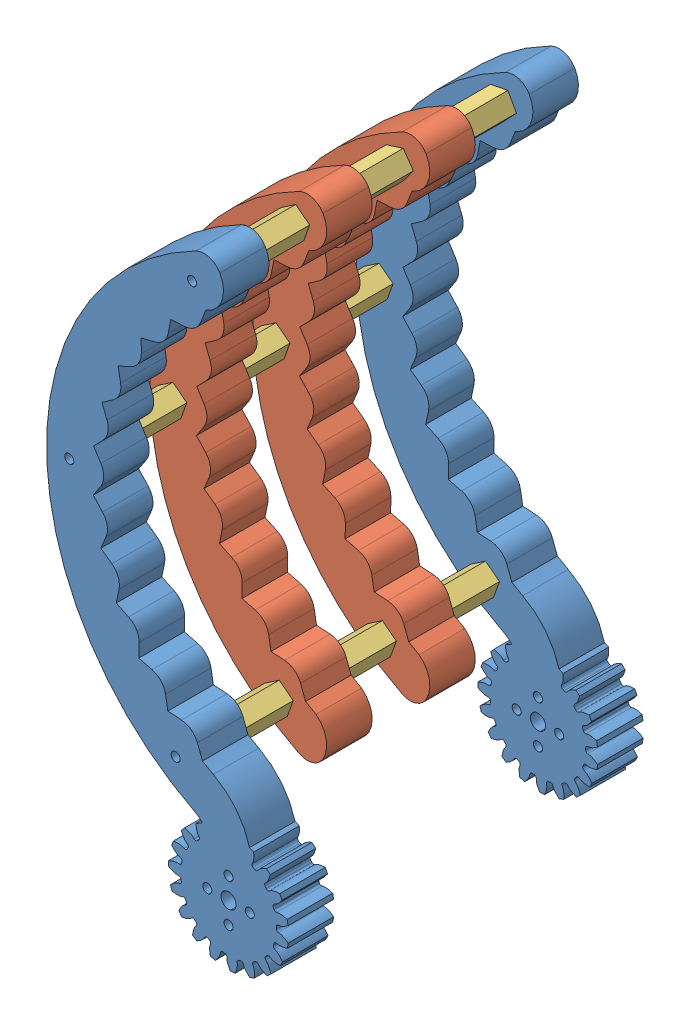
SolidWorks assembly 装配体_左爪子, configuration Default. Lengths in mm.
Overall size (79.66 200.49 117).
13 component instances, 3 part files, 27 mates.
Components (placement in the parent):
- 1_1.左爪子表面_打印两个-1: 1_1.左爪子表面_打印两个 [Varsayılan] at origin size (79.66 200.49 15)
- 1_3.爪子中间_打印四个-1: 1_3.爪子中间_打印四个 [Varsayılan] at (-2.9202 8.1355 -34) size (58.35 161.77 15)
- 2.铜柱连接件-1: 2.铜柱连接件 [Varsayılan] at (-28.6612 -59.3847 -21.5) x (0.366858 -0.930277 0) z (0 0 1) size (9.37 9.17 19)
- 2.铜柱连接件-2: 2.铜柱连接件 [Varsayılan] at (-63.7311 8.1181 -21.5) x (0.366858 -0.930277 0) z (0 0 1) size (9.37 9.17 19)
- 2.铜柱连接件-3: 2.铜柱连接件 [Varsayılan] at (-23.232 79.1263 -21.5) x (0.366858 -0.930277 0) z (0 0 1) size (9.37 9.17 19)
- 2.铜柱连接件-4: 2.铜柱连接件 [Varsayılan] at (-23.232 79.1263 -55.5) x (-0.923835 -0.38279 0) z (0 0 1) size (9.37 9.17 19)
- 2.铜柱连接件-5: 2.铜柱连接件 [Varsayılan] at (-63.7311 8.1181 -55.5) x (0.366858 -0.930277 0) z (0 0 1) size (9.37 9.17 19)
- 2.铜柱连接件-6: 2.铜柱连接件 [Varsayılan] at (-28.6612 -59.3847 -55.5) x (0.366858 -0.930277 0) z (0 0 1) size (9.37 9.17 19)
- 2.铜柱连接件-7: 2.铜柱连接件 [Varsayılan] at (-28.6612 -59.3847 -89.5) x (0.366858 -0.930277 0) z (0 0 1) size (9.37 9.17 19)
- 2.铜柱连接件-8: 2.铜柱连接件 [Varsayılan] at (-23.232 79.1263 -89.5) x (-0.960896 -0.276909 0) z (0 0 1) size (9.37 9.17 19)
- 2.铜柱连接件-9: 2.铜柱连接件 [Varsayılan] at (-63.7311 8.1181 -89.5) x (0.366858 -0.930277 0) z (0 0 1) size (9.37 9.17 19)
- 1_3.爪子中间_打印四个-2: 1_3.爪子中间_打印四个 [Varsayılan] at (-2.9202 8.1355 -68) size (58.35 161.77 15)
- 1_1.左爪子表面_打印两个-2: 1_1.左爪子表面_打印两个 [Varsayılan] at (0 0 -102) size (79.66 200.49 15)
Mates (geometry in assembly coordinates):
- 同心1: concentric aligned: cylinder of 1_1.左爪子表面_打印两个-1 through (-28.6612 -59.3847 -1) axis (0 0 -1) radius 1.5; cylinder of 2.铜柱连接件-1 through (-28.6612 -59.3847 -2.5) axis (0 0 -1) radius 2.5
- 重合1: coincident anti-aligned: plane of 1_1.左爪子表面_打印两个-1 through (-26.033 70.9061 -2.5) normal (0 0 -1); plane of 2.铜柱连接件-1 through (-28.6612 -59.3847 -2.5) normal (0 0 1)
- 重合2: coincident anti-aligned: plane of 1_1.左爪子表面_打印两个-1 through (-26.033 70.9061 -2.5) normal (0 0 -1); plane of 2.铜柱连接件-2 through (-63.7311 8.1181 -2.5) normal (0 0 1)
- 同心2: concentric anti-aligned: cylinder of 1_1.左爪子表面_打印两个-1 through (-63.7311 8.1181 -1) axis (0 0 -1) radius 1.5; circle of 2.铜柱连接件-2
- 同心3: concentric aligned: cylinder of 1_1.左爪子表面_打印两个-1 through (-23.232 79.1263 -1) axis (0 0 -1) radius 1.5; cylinder of 2.铜柱连接件-3 through (-23.232 79.1263 -2.5) axis (0 0 -1) radius 2.5
- 重合3: coincident anti-aligned: plane of 1_1.左爪子表面_打印两个-1 through (-26.033 70.9061 -2.5) normal (0 0 -1); plane of 2.铜柱连接件-3 through (-23.232 79.1263 -2.5) normal (0 0 1)
- 重合4: coincident anti-aligned: plane of 1_3.爪子中间_打印四个-1 through (-26.033 70.9061 -21.5) normal (0 0 1); plane of 2.铜柱连接件-3 through (-23.232 79.1263 -21.5) normal (0 0 -1)
- 同心4: concentric aligned: cylinder of 1_3.爪子中间_打印四个-1 through (-23.232 79.1263 -35) axis (0 0 -1) radius 1.5; cylinder of 2.铜柱连接件-3 through (-23.232 79.1263 -2.5) axis (0 0 -1) radius 2.5
- 同心5: concentric aligned: cylinder of 1_3.爪子中间_打印四个-1 through (-63.7311 8.1181 -35) axis (0 0 -1) radius 1.5; cylinder of 2.铜柱连接件-2 through (-63.7311 8.1181 -2.5) axis (0 0 -1) radius 2.5
- 同心6: concentric aligned: cylinder of 1_3.爪子中间_打印四个-1 through (-23.232 79.1263 -35) axis (0 0 -1) radius 1.5; cylinder of 2.铜柱连接件-4 through (-23.232 79.1263 -36.5) axis (0 0 -1) radius 2.5
- 重合5: coincident anti-aligned: plane of 1_3.爪子中间_打印四个-1 through (-26.033 70.9061 -36.5) normal (0 0 -1); plane of 2.铜柱连接件-4 through (-23.232 79.1263 -36.5) normal (0 0 1)
- 重合6: coincident aligned: point of 1_3.爪子中间_打印四个-1; moEndPointRef_w of 2.铜柱连接件-5
- 同心7: concentric aligned: cylinder of 1_3.爪子中间_打印四个-1 through (-63.7311 8.1181 -35) axis (0 0 -1) radius 1.5; cylinder of 2.铜柱连接件-5 through (-63.7311 8.1181 -36.5) axis (0 0 -1) radius 2.5
- 同心8: concentric aligned: cylinder of 1_3.爪子中间_打印四个-1 through (-28.6612 -59.3847 -35) axis (0 0 -1) radius 1.5; cylinder of 2.铜柱连接件-6 through (-28.6612 -59.3847 -36.5) axis (0 0 -1) radius 2.5
- 重合7: coincident: plane of 1_3.爪子中间_打印四个-1 through (-26.033 70.9061 -36.5) normal (0 0 -1); point of 2.铜柱连接件-6
- 同心9: concentric aligned: circle of 2.铜柱连接件-4; circle of 1_3.爪子中间_打印四个-2
- 重合8: coincident anti-aligned: plane of 2.铜柱连接件-4 through (-23.232 79.1263 -55.5) normal (0 0 -1); plane of 1_3.爪子中间_打印四个-2 through (-26.033 70.9061 -55.5) normal (0 0 1)
- 同心10: concentric aligned: circle of 2.铜柱连接件-5; circle of 1_3.爪子中间_打印四个-2
- 同心11: concentric anti-aligned: circle of 2.铜柱连接件-8; cylinder of 1_3.爪子中间_打印四个-2 through (-23.232 79.1263 -69) axis (0 0 -1) radius 1.5
- 重合9: coincident anti-aligned: plane of 2.铜柱连接件-8 through (-23.232 79.1263 -70.5) normal (0 0 1); plane of 1_3.爪子中间_打印四个-2 through (-26.033 70.9061 -70.5) normal (0 0 -1)
- 重合10: coincident anti-aligned: plane of 2.铜柱连接件-9 through (-63.7311 8.1181 -70.5) normal (0 0 1); plane of 1_3.爪子中间_打印四个-2 through (-26.033 70.9061 -70.5) normal (0 0 -1)
- 同心12: concentric aligned: circle of 2.铜柱连接件-9; circle of 1_3.爪子中间_打印四个-2
- 重合11: coincident anti-aligned: plane of 2.铜柱连接件-7 through (-28.6612 -59.3847 -70.5) normal (0 0 1); plane of 1_3.爪子中间_打印四个-2 through (-26.033 70.9061 -70.5) normal (0 0 -1)
- 同心13: concentric anti-aligned: cylinder of 2.铜柱连接件-7 through (-28.6612 -59.3847 -70.5) axis (0 0 -1) radius 2.5; circle of 1_3.爪子中间_打印四个-2
- 重合12: coincident anti-aligned: plane of 2.铜柱连接件-8 through (-23.232 79.1263 -89.5) normal (0 0 -1); plane of 1_1.左爪子表面_打印两个-2 through (-26.033 70.9061 -89.5) normal (0 0 1)
- 同心14: concentric aligned: cylinder of 2.铜柱连接件-8 through (-23.232 79.1263 -70.5) axis (0 0 -1) radius 2.5; cylinder of 1_1.左爪子表面_打印两个-2 through (-23.232 79.1263 -103) axis (0 0 -1) radius 1.5
- 同心15: concentric anti-aligned: cylinder of 2.铜柱连接件-9 through (-63.7311 8.1181 -70.5) axis (0 0 -1) radius 2.5; circle of 1_1.左爪子表面_打印两个-2
